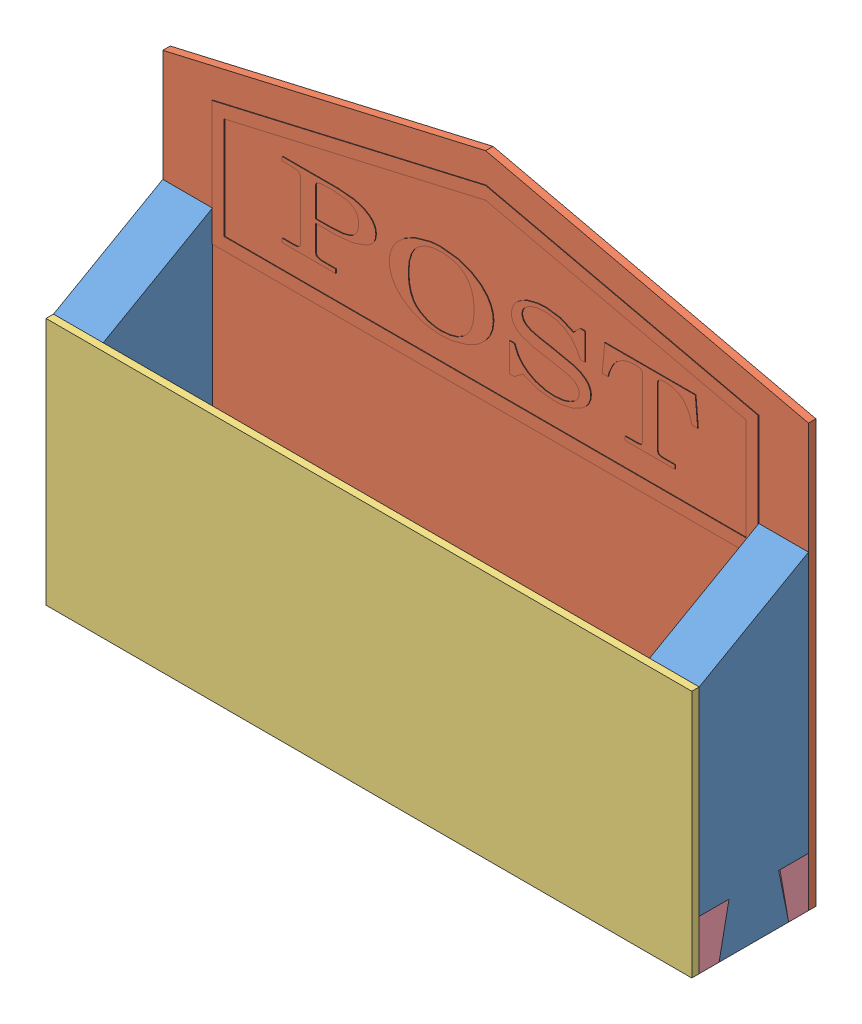
SolidWorks assembly Letter Holder, configuration Default. Lengths in mm.
Overall size (260 200 50).
5 component instances, 4 part files, 9 mates.
Components (placement in the parent):
- GABLE-1: GABLE [Default] at (-110 62.5 0) x (0 0 1) z (-1 0 0) size (44 125 20)
- GABLE-2: GABLE [Default] at (130 62.5 0) x (0 0 1) z (-1 0 0) size (44 125 20)
- BACK COVER-1: BACK COVER [Default] at (0 100 -25) size (260 200 3.25)
- FORNT COVER-1: FORNT COVER [Default] at (0 50 22) size (260 100 3)
- Bottom-1: Bottom [Default] at (0 10 0) size (260 20 44)
Mates (geometry in assembly coordinates):
- Coincident7: coincident anti-aligned: plane of GABLE-2 through (110 125 -22) normal (0 0 -1); plane of BACK COVER-1 through (-130 0 -22) normal (0 0 1)
- Coincident8: coincident aligned: plane of GABLE-2 through (130 0 -22) normal (1 0 0); plane of BACK COVER-1 through (130 200 -22) normal (1 0 0)
- Coincident10: coincident anti-aligned: plane of GABLE-2 through (110 125 22) normal (0 0 1); plane of FORNT COVER-1 through (-130 0 22) normal (0 0 -1)
- Coincident11: coincident aligned: plane of GABLE-2 through (130 0 -22) normal (1 0 0); plane of FORNT COVER-1 through (130 100 25) normal (1 0 0)
- Coincident12: coincident aligned: plane of GABLE-2 through (130 0 -22) normal (1 0 0); plane of Bottom-1 through (130 0 22) normal (1 0 0)
- Coincident13: coincident anti-aligned: plane of GABLE-2 through (110 0 -22) normal (-1 0 0); plane of Bottom-1 through (110 20 10) normal (1 0 0)
- Coincident14: coincident anti-aligned: plane of GABLE-2 through (110 0 -22) normal (-1 0 0); plane of Bottom-1 through (110 20 10) normal (1 0 0)
- Coincident15: coincident anti-aligned: plane of GABLE-2 through (130 20 10) normal (0 0.196116 0.980581); plane of Bottom-1 through (110 0 14) normal (0 -0.196116 -0.980581)
- Coincident16: coincident aligned: plane of GABLE-2 through (110 0 -22) normal (0 -1 0); plane of Bottom-1 through (130 0 22) normal (0 -1 0)
